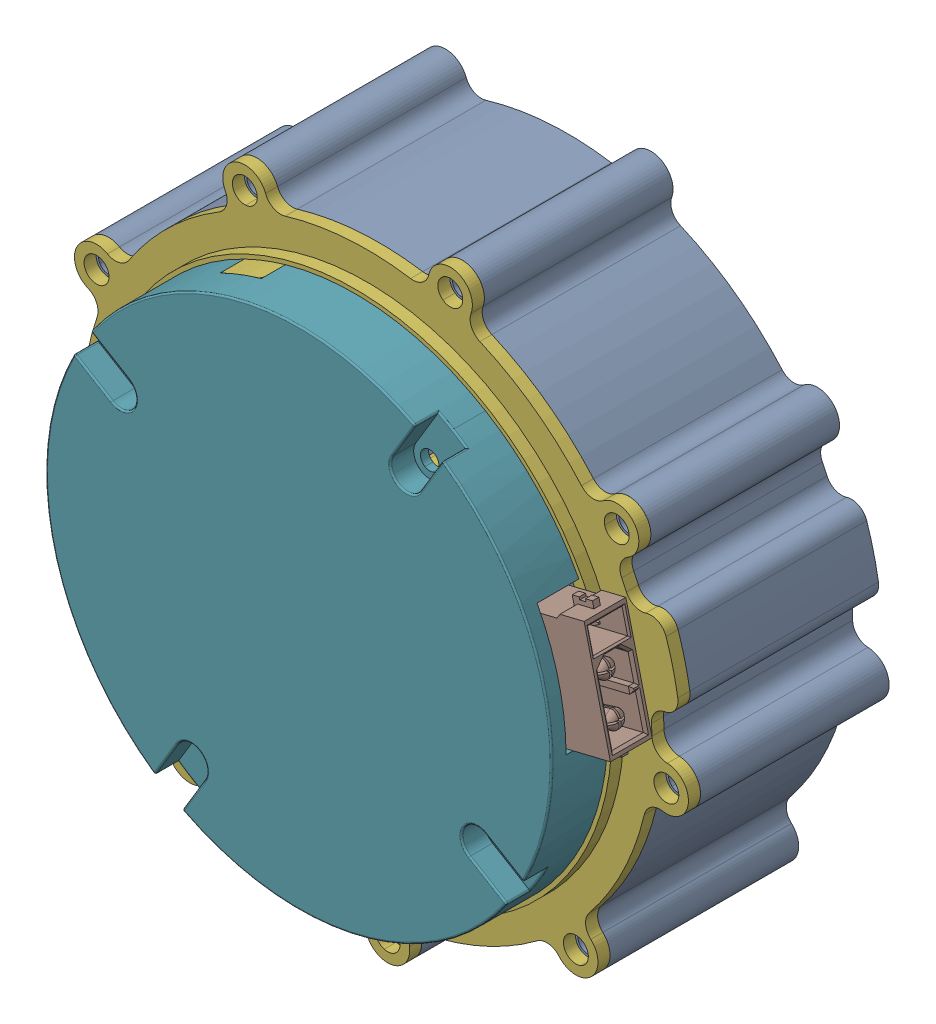
SolidWorks assembly 3_1_02_067_0003_ASM_ASM_1_ASM_1_ASM.stp, configuration 默认. Lengths in mm.
Overall size (96.28 96.17 36.5).
11 component instances, 8 part files, 0 mates.
Components (placement in the parent):
- 3_1_02_067_0003_ASM_1_ASM_1_ASM_ASM.stp-1: 3_1_02_067_0003_ASM_1_ASM_1_ASM_ASM.stp [默认] at origin size (96.28 96.17 36.5)
  - 1_1_06_EB673-504_1_1_1_1_1.stp-1: 1_1_06_EB673-504_1_1_1_1_1.stp [默认] at (39.8324 39.833 -22) size (79.19 78.95 25.5)
  - 1_2_04_670601_1_1_1_1_1.stp-1: 1_2_04_670601_1_1_1_1_1.stp [默认] at (93.9161 79.9966 -44) size (37 37 4)
  - 1_1_02_EB671-500_1_1_1_1_1.stp-1: 1_1_02_EB671-500_1_1_1_1_1.stp [默认] at (93.9161 79.9966 -44.4) x (-0.960973 0.276644 0) z (0 0 1) size (33 33 8.5)
  - 1_2_04_694000_1_1_1_1_1.stp-1: 1_2_04_694000_1_1_1_1_1.stp [默认] at (93.9161 79.9966 -44.5) size (11 11 4)
  - 1_2_06_000213_1_1_1_1_1.stp-1: 1_2_06_000213_1_1_1_1_1.stp [默认] at (93.9161 79.9966 -45.5) size (38.8 36.2 1.5)
  - 1_1_31_QT-642_1_1_1_1_1.stp-1: 1_1_31_QT-642_1_1_1_1_1.stp [默认] at (93.9161 79.9966 -22) x (-0.970555 -0.24088 0) z (0 0 -1) size (79.5 79.36 6)
  - 1_1_06_EB673-502_1_1_1_1_1.stp-1: 1_1_06_EB673-502_1_1_1_1_1.stp [默认] at (93.9161 79.9966 -13) x (-0.515958 -0.856614 0) z (0 0 -1) size (63 63 8)
- 0518_ASM_2_ASM_1_ASM_1_ASM_1_AS_ASM.stp-1: 0518_ASM_2_ASM_1_ASM_1_ASM_1_AS_ASM.stp [默认] at (93.9161 79.9966 -17.235) x (0.235897 -0.971778 0) z (0 0 1) size (15.5 11.3 5.2)
  - 12345_ASM_1_ASM_2_ASM_1_ASM_1_A_ASM.stp-1: 12345_ASM_1_ASM_2_ASM_1_ASM_1_A_ASM.stp [默认] at origin size (15.5 11.3 5.2)
    - DUANZI_1_3_1_1_1_1_1_1.stp-1: DUANZI_1_3_1_1_1_1_1_1.stp [默认] at (-0.1798 16.5474 0.4329) x (0 0 -1) z (0 1 0) size (5.2 15.5 11.3)
